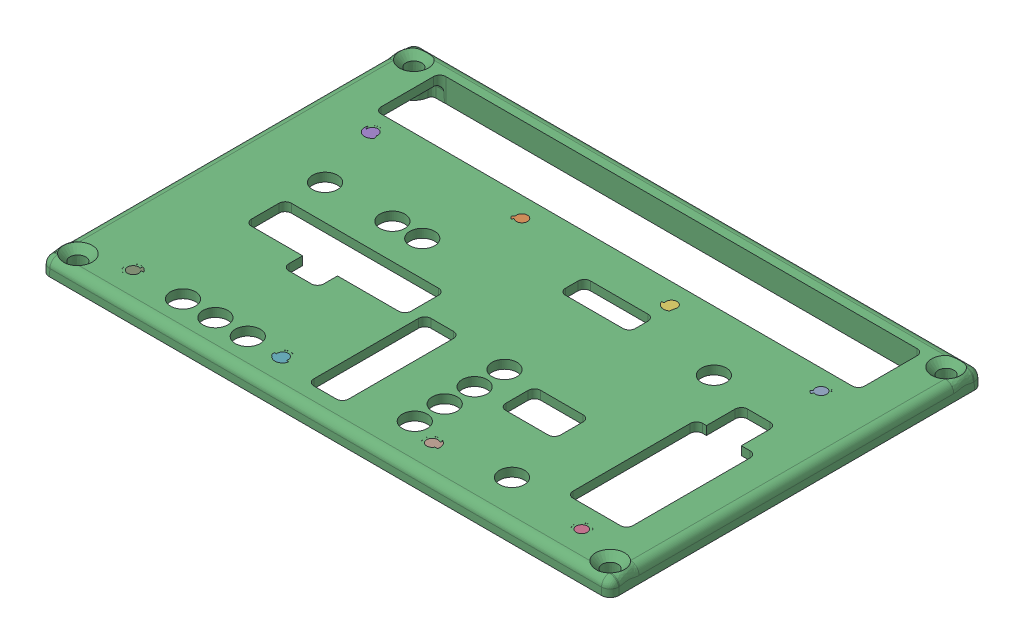
SolidWorks assembly 1590J Lid - Modified, configuration Default. Lengths in mm.
Overall size (145 6.56 95).
9 component instances, 2 part files, 0 mates.
Components (placement in the parent):
- PEM FHS-440-4ZI-1: PEM FHS-440-4ZI [Default] at (57.15 4 -21.59) x (0 -1 0) z (0 0 1) size (6.35 4.47 4.47)
- PEM FHS-440-4ZI-2: PEM FHS-440-4ZI [Default] at (-19.05 4 -21.59) x (0 -1 0) z (0 0 1) size (6.35 4.47 4.47)
- 1590J Lid-1: 1590J Lid [Default] x (1 0 0) z (0 -1 0) size (145 95 6.25)
- PEM FHS-440-4ZI-3: PEM FHS-440-4ZI [Default] at (57.15 4 39.37) x (0 -1 0) z (0 0 1) size (6.35 4.47 4.47)
- PEM FHS-440-4ZI-4: PEM FHS-440-4ZI [Default] at (-57.15 4 -21.59) x (0 -1 0) z (0 0 1) size (6.35 4.47 4.47)
- PEM FHS-440-4ZI-5: PEM FHS-440-4ZI [Default] at (19.05 4 -21.59) x (0 -1 0) z (0 0 1) size (6.35 4.47 4.47)
- PEM FHS-440-4ZI-6: PEM FHS-440-4ZI [Default] at (-19.05 4 39.37) x (0 -1 0) z (0 0 1) size (6.35 4.47 4.47)
- PEM FHS-440-4ZI-7: PEM FHS-440-4ZI [Default] at (19.05 4 39.37) x (0 -1 0) z (0 0 1) size (6.35 4.47 4.47)
- PEM FHS-440-4ZI-8: PEM FHS-440-4ZI [Default] at (-57.15 4 39.37) x (0 -1 0) z (0 0 1) size (6.35 4.47 4.47)
